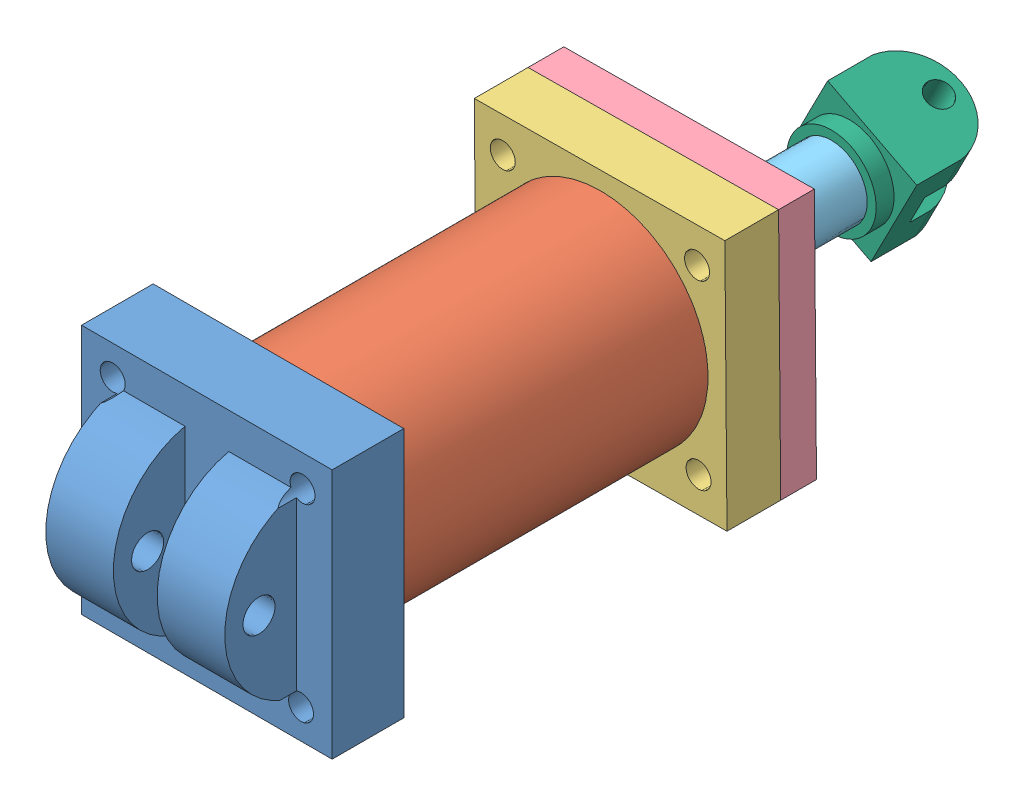
SolidWorks assembly Assem2, configuration Default. Lengths in mm.
Overall size (74.42 74.42 224.27).
6 component instances, 6 part files, 13 mates.
Components (placement in the parent):
- Part4-1: Part4 [Default] at (-98.5654 36.5988 91.1193) size (70 70 40)
- Part5-1: Part5 [Default] at (-98.5654 36.5988 -3.8807) x (0.959853 -0.280503 0) z (0 0 1) size (60 60 100)
- Part6-1: Part6 [Default] at (-98.5654 36.5988 -13.8807) x (-0.008415 0.999965 0) z (0 0 1) size (70 70 15)
- Part7-3: Part7 [Default] at (-98.5654 36.5988 -23.8807) x (0.999965 0.008415 0) z (0 0 1) size (70 70 25)
- Part8-1: Part8 [Default] at (-98.5654 36.5988 -68.3483) x (-0.331262 0.943539 0) z (0.943539 0.331262 0) size (50 120 50)
- Part9-1: Part9 [Default] at (-98.5654 36.5988 -63.3483) x (0.456618 0.889663 0) z (0 0 -1) size (28 28 29.8)
Mates (geometry in assembly coordinates):
- Parallel3: parallel anti-aligned: plane of Part4-1 through (-98.5654 36.5988 96.1193) normal (0 0 -1); plane of Part5-1 through (-98.5654 36.5988 96.1193) normal (0 0 1)
- Concentric1: concentric aligned: cylinder of Part4-1 through (-98.5654 36.5988 96.1193) axis (0 0 -1) radius 30; cylinder of Part5-1 through (-98.5654 36.5988 96.1193) axis (0 0 -1) radius 30
- Coincident8: coincident anti-aligned: plane of Part4-1 through (-98.5654 36.5988 96.1193) normal (0 0 -1); plane of Part5-1 through (-98.5654 36.5988 96.1193) normal (0 0 1)
- Concentric2: concentric anti-aligned: cylinder of Part5-1 through (-98.5654 36.5988 96.1193) axis (0 0 -1) radius 30; cylinder of Part6-1 through (-98.5654 36.5988 -3.8807) axis (0 0 1) radius 30
- Coincident9: coincident anti-aligned: plane of Part5-1 through (-98.5654 36.5988 -3.8807) normal (0 0 -1); plane of Part6-1 through (-98.5654 36.5988 -3.8807) normal (0 0 1)
- Coincident16: coincident anti-aligned: plane of Part6-1 through (-98.5654 36.5988 -13.8807) normal (0 0 -1); plane of Part7-3 through (-98.5654 36.5988 -13.8807) normal (0 0 1)
- Coincident17: coincident aligned: plane of Part6-1 through (-63.8612 71.8921 1.1193) normal (-0.008415 0.999965 0); plane of Part7-3 through (-133.8587 71.303 -13.8807) normal (-0.008415 0.999965 0)
- Coincident18: coincident aligned: plane of Part6-1 through (-63.2721 1.8945 1.1193) normal (0.999965 0.008415 0); plane of Part7-3 through (-63.8612 71.8921 -13.8807) normal (0.999965 0.008415 0)
- Concentric3: concentric anti-aligned: cylinder of Part7-3 through (-98.5654 36.5988 -23.8807) axis (0 0 1) radius 10; cylinder of Part8-1 through (-98.5654 36.5988 31.6517) axis (0 0 -1) radius 10
- Concentric4: concentric aligned: cylinder of Part5-1 through (-98.5654 36.5988 96.1193) axis (0 0 -1) radius 25; cylinder of Part8-1 through (-98.5654 36.5988 51.6517) axis (0 0 -1) radius 25
- Parallel4: parallel anti-aligned: plane of Part6-1 through (-98.5654 36.5988 1.1193) normal (0 0 1); plane of Part8-1 through (-98.5654 36.5988 31.6517) normal (0 0 -1)
- Concentric6: concentric anti-aligned: cylinder of Part8-1 through (-98.5654 36.5988 31.6517) axis (0 0 -1) radius 10; cylinder of Part9-1 through (-98.5654 36.5988 -68.3483) axis (0 0 1) radius 10
- Coincident23: coincident anti-aligned: plane of Part8-1 through (-98.5654 36.5988 -68.3483) normal (0 0 -1); plane of Part9-1 through (-98.5654 36.5988 -68.3483) normal (0 0 1)
